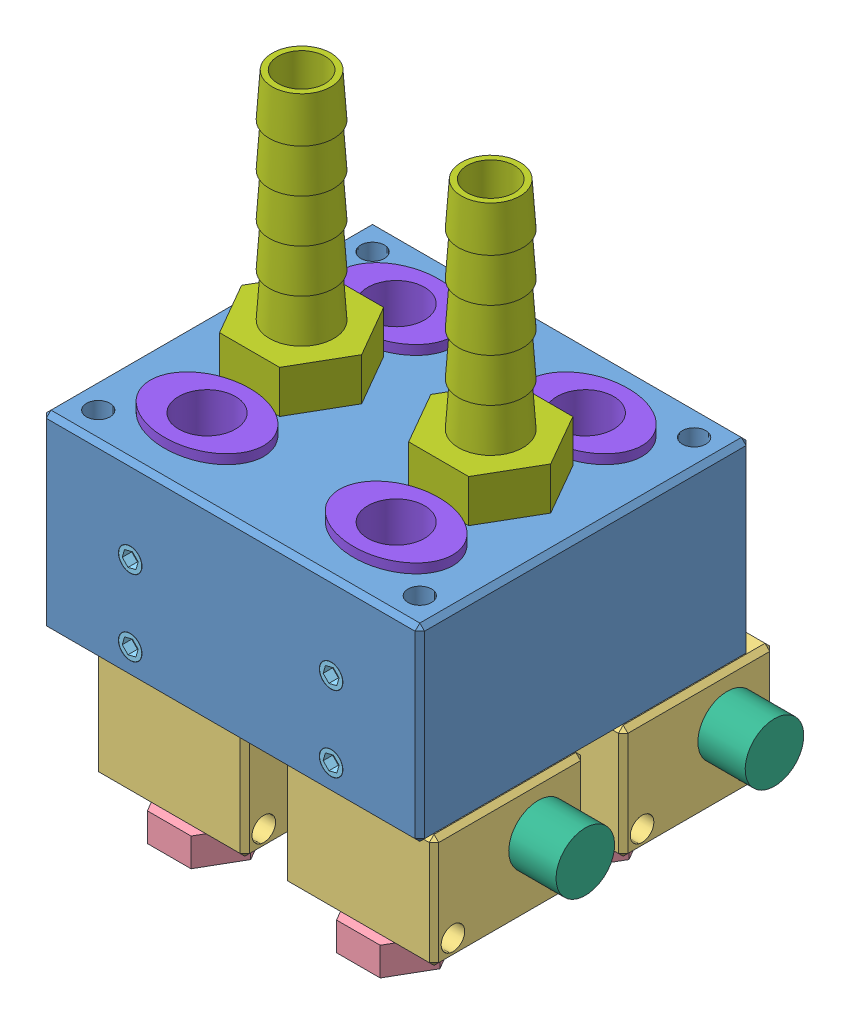
SolidWorks assembly Kraken, configuration Default. Lengths in mm.
Overall size (66 67 39.5).
35 component instances, 8 part files, 76 mates.
Components (placement in the parent):
- Kraken Cooling Block-1: Kraken Cooling Block [Default] at origin size (40 20 35)
- Kraken Heat Break-1: Kraken Heat Break [Default] at (-10 3.2 10) x (-0.959277 0 -0.282467) z (0.282467 0 -0.959277) size (7 20.6 7)
- E3D Heat Block-1: E3D Heat Block [Default] at (-10 -14.1 6) x (0 0 -1) z (1 0 0) size (16 12 16)
- E3D Nozzle-1: E3D Nozzle [Default] at (-10 -17.6 10) size (9.24 12.5 8)
- socket set screw cone point_am-2: socket set screw cone point_am [B18.3.6M - M3 x 0.5 x 3 Hex Socket Cone Pt. SS --N] at (-10 -14.1 4) x (0 1 0) z (0.271788 0 0.962357) size (3 3 3)
- cartridge heater-1: cartridge heater [Default] at (-12 -7.1 3) size (32 6.2 6.2)
- socket set screw cone point_am-4: socket set screw cone point_am [B18.3.6M - M3 x 0.5 x 3 Hex Socket Cone Pt. SS --N] at (10.6221 11 17.5) x (0 0 -1) z (0.271788 0.962357 0) size (3 3 3)
- socket set screw cone point_am-5: socket set screw cone point_am [B18.3.6M - M3 x 0.5 x 3 Hex Socket Cone Pt. SS --N] at (10.6221 3 17.5) x (0 0 -1) z (0.271788 0.962357 0) size (3 3 3)
- socket set screw cone point_am-6: socket set screw cone point_am [B18.3.6M - M3 x 0.5 x 3 Hex Socket Cone Pt. SS --N] at (-10.6221 11 17.5) x (0 0 -1) z (0.271788 0.962357 0) size (3 3 3)
- socket set screw cone point_am-7: socket set screw cone point_am [B18.3.6M - M3 x 0.5 x 3 Hex Socket Cone Pt. SS --N] at (-10.6221 3 17.5) x (0 0 -1) z (0.271788 0.962357 0) size (3 3 3)
- socket set screw cone point_am-8: socket set screw cone point_am [B18.3.6M - M3 x 0.5 x 3 Hex Socket Cone Pt. SS --N] at (-10.6221 3 -17.5) x (0 0 1) z (0.271788 -0.962357 0) size (3 3 3)
- socket set screw cone point_am-9: socket set screw cone point_am [B18.3.6M - M3 x 0.5 x 3 Hex Socket Cone Pt. SS --N] at (-10.6221 11 -17.5) x (0 0 1) z (0.271788 -0.962357 0) size (3 3 3)
- socket set screw cone point_am-10: socket set screw cone point_am [B18.3.6M - M3 x 0.5 x 3 Hex Socket Cone Pt. SS --N] at (10.6221 11 -17.5) x (0 0 1) z (0.271788 -0.962357 0) size (3 3 3)
- socket set screw cone point_am-11: socket set screw cone point_am [B18.3.6M - M3 x 0.5 x 3 Hex Socket Cone Pt. SS --N] at (10.6221 3 -17.5) x (0 0 1) z (0.271788 -0.962357 0) size (3 3 3)
- E3D Nozzle-5: E3D Nozzle [Default] at (10 -17.6 10) size (9.24 12.5 8)
- cartridge heater-5: cartridge heater [Default] at (12 -7.1 3) x (-1 0 0) z (0 0.924225 0.381849) size (32 6.2 6.2)
- socket set screw cone point_am-15: socket set screw cone point_am [B18.3.6M - M3 x 0.5 x 3 Hex Socket Cone Pt. SS --N] at (10 -14.1 4) x (0 1 0) z (0.271788 0 0.962357) size (3 3 3)
- E3D Heat Block-5: E3D Heat Block [Default] at (10 -14.1 6) x (0 0 -1) z (1 0 0) size (16 12 16)
- Kraken Heat Break-12: Kraken Heat Break [Default] at (10 3.2 10) x (-0.959277 0 -0.282467) z (0.282467 0 -0.959277) size (7 20.6 7)
- E3D Nozzle-6: E3D Nozzle [Default] at (10 -17.6 -10) size (9.24 12.5 8)
- cartridge heater-6: cartridge heater [Default] at (12 -7.1 -17) x (-1 0 0) z (0 0.924225 0.381849) size (32 6.2 6.2)
- socket set screw cone point_am-16: socket set screw cone point_am [B18.3.6M - M3 x 0.5 x 3 Hex Socket Cone Pt. SS --N] at (10 -14.1 -16) x (0 1 0) z (0.271788 0 0.962357) size (3 3 3)
- E3D Heat Block-6: E3D Heat Block [Default] at (10 -14.1 -14) x (0 0 -1) z (1 0 0) size (16 12 16)
- Kraken Heat Break-13: Kraken Heat Break [Default] at (10 3.2 -10) x (-0.959277 0 -0.282467) z (0.282467 0 -0.959277) size (7 20.6 7)
- E3D Nozzle-7: E3D Nozzle [Default] at (-10 -17.6 -10) size (9.24 12.5 8)
- cartridge heater-7: cartridge heater [Default] at (-12 -7.1 -17) size (32 6.2 6.2)
- socket set screw cone point_am-17: socket set screw cone point_am [B18.3.6M - M3 x 0.5 x 3 Hex Socket Cone Pt. SS --N] at (-10 -14.1 -16) x (0 1 0) z (0.271788 0 0.962357) size (3 3 3)
- E3D Heat Block-7: E3D Heat Block [Default] at (-10 -14.1 -14) x (0 0 -1) z (1 0 0) size (16 12 16)
- Kraken Heat Break-14: Kraken Heat Break [Default] at (-10 3.2 -10) x (-0.959277 0 -0.282467) z (0.282467 0 -0.959277) size (7 20.6 7)
- E3D Barbed fitting-1: E3D Barbed fitting [4810T221] at (-10 23.175 0) x (0 1 0) z (0 0 1) size (35.43 12.7 11)
- E3D Barbed fitting-2: E3D Barbed fitting [4810T221] at (10 23.175 0) x (0 1 0) z (-0.001728 0 0.999999) size (35.43 12.7 11)
- Kraken Compression Coupling-1: Kraken Compression Coupling [Default] at (10 20 -10) size (12 6.5 9)
- Kraken Compression Coupling-2: Kraken Compression Coupling [Default] at (-10 20 -10) size (12 6.5 9)
- Kraken Compression Coupling-3: Kraken Compression Coupling [Default] at (-10 20 10) size (12 6.5 9)
- Kraken Compression Coupling-4: Kraken Compression Coupling [Default] at (10 20 10) size (12 6.5 9)
Mates (geometry in assembly coordinates):
- Parallel1: parallel aligned: plane of Kraken Cooling Block-1 through (-20 20 17.5) normal (0 0 1); plane of E3D Heat Block-1 through (-2 -2.1 14) normal (0 0 1)
- Concentric10: concentric aligned: cylinder of E3D Heat Block-1 through (-10 -14.1 4) axis (0 -1 0) radius 1.25; cylinder of socket set screw cone point_am-2 through (-10 -26.8 4) axis (0 -1 0) radius 1.5
- Coincident13: coincident aligned: plane of E3D Heat Block-1 through (-10 -14.1 6) normal (0 -1 0); plane of socket set screw cone point_am-2 through (-10 -14.1 4) normal (0 -1 0)
- Concentric11: concentric anti-aligned: cylinder of E3D Heat Block-1 through (-18 -7.1 3) axis (1 0 0) radius 3.1; cylinder of cartridge heater-1 through (-23 -7.1 3) axis (-1 0 0) radius 3.1
- Concentric13: concentric aligned: cylinder of Kraken Cooling Block-1 through (10.6221 11 17.5) axis (0 0 1) radius 1.25; cylinder of socket set screw cone point_am-4 through (10.6221 11 30.2) axis (0 0 1) radius 1.5
- Coincident16: coincident aligned: plane of Kraken Cooling Block-1 through (-20 20 17.5) normal (0 0 1); plane of socket set screw cone point_am-4 through (10.6221 11 17.5) normal (0 0 1)
- Concentric14: concentric aligned: cylinder of Kraken Cooling Block-1 through (10.6221 3 17.5) axis (0 0 1) radius 1.25; cylinder of socket set screw cone point_am-5 through (10.6221 3 30.2) axis (0 0 1) radius 1.5
- Coincident17: coincident aligned: plane of Kraken Cooling Block-1 through (-20 20 17.5) normal (0 0 1); plane of socket set screw cone point_am-5 through (10.6221 3 17.5) normal (0 0 1)
- Concentric15: concentric aligned: cylinder of Kraken Cooling Block-1 through (-10.6221 11 17.5) axis (0 0 1) radius 1.25; cylinder of socket set screw cone point_am-6 through (-10.6221 11 30.2) axis (0 0 1) radius 1.5
- Coincident18: coincident aligned: plane of Kraken Cooling Block-1 through (-20 20 17.5) normal (0 0 1); plane of socket set screw cone point_am-6 through (-10.6221 11 17.5) normal (0 0 1)
- Concentric16: concentric aligned: cylinder of Kraken Cooling Block-1 through (-10.6221 3 17.5) axis (0 0 1) radius 1.25; cylinder of socket set screw cone point_am-7 through (-10.6221 3 30.2) axis (0 0 1) radius 1.5
- Coincident19: coincident aligned: plane of Kraken Cooling Block-1 through (-20 20 17.5) normal (0 0 1); plane of socket set screw cone point_am-7 through (-10.6221 3 17.5) normal (0 0 1)
- Concentric17: concentric aligned: cylinder of Kraken Cooling Block-1 through (-10.6221 3 -17.5) axis (0 0 -1) radius 1.25; cylinder of socket set screw cone point_am-8 through (-10.6221 3 -30.2) axis (0 0 -1) radius 1.5
- Coincident20: coincident aligned: plane of Kraken Cooling Block-1 through (-20 20 -17.5) normal (0 0 -1); plane of socket set screw cone point_am-8 through (-10.6221 3 -17.5) normal (0 0 -1)
- Concentric18: concentric aligned: cylinder of Kraken Cooling Block-1 through (-10.6221 11 -17.5) axis (0 0 -1) radius 1.25; cylinder of socket set screw cone point_am-9 through (-10.6221 11 -30.2) axis (0 0 -1) radius 1.5
- Coincident21: coincident aligned: plane of Kraken Cooling Block-1 through (-20 20 -17.5) normal (0 0 -1); plane of socket set screw cone point_am-9 through (-10.6221 11 -17.5) normal (0 0 -1)
- Concentric19: concentric aligned: cylinder of Kraken Cooling Block-1 through (10.6221 11 -17.5) axis (0 0 -1) radius 1.25; cylinder of socket set screw cone point_am-10 through (10.6221 11 -30.2) axis (0 0 -1) radius 1.5
- Coincident22: coincident aligned: plane of Kraken Cooling Block-1 through (-20 20 -17.5) normal (0 0 -1); plane of socket set screw cone point_am-10 through (10.6221 11 -17.5) normal (0 0 -1)
- Concentric20: concentric aligned: cylinder of Kraken Cooling Block-1 through (10.6221 3 -17.5) axis (0 0 -1) radius 1.25; cylinder of socket set screw cone point_am-11 through (10.6221 3 -30.2) axis (0 0 -1) radius 1.5
- Coincident23: coincident aligned: plane of Kraken Cooling Block-1 through (-20 20 -17.5) normal (0 0 -1); plane of socket set screw cone point_am-11 through (10.6221 3 -17.5) normal (0 0 -1)
- Distance1: distance = 1 mm aligned: plane of cartridge heater-1 through (-1 -7.1 0.4) normal (1 0 0); plane of E3D Heat Block-1 through (-2 -2.1 14) normal (1 0 0)
- Concentric21: concentric aligned: cylinder of Kraken Heat Break-1 through (-10 -7.1 10) axis (0 -1 0) radius 3; cylinder of E3D Nozzle-1 through (-10 -19.6 10) axis (0 -1 0) radius 3
- Coincident25: coincident anti-aligned: plane of Kraken Heat Break-1 through (-10.9593 -7.1 9.7175) normal (0 -1 0); plane of E3D Nozzle-1 through (-10 -7.1 10) normal (0 1 0)
- Concentric22: concentric anti-aligned: cylinder of Kraken Heat Break-1 through (-10 -7.1 10) axis (0 -1 0) radius 3; cylinder of E3D Heat Block-1 through (-10 -2.1 10) axis (0 1 0) radius 2.5
- Coincident26: coincident aligned: plane of Kraken Heat Break-1 through (-12.8778 -2.1 9.1526) normal (0 1 0); plane of E3D Heat Block-1 through (-10 -2.1 6) normal (0 1 0)
- Concentric23: concentric aligned: cylinder of Kraken Cooling Block-1 through (-10 0 10) axis (0 -1 0) radius 3.5; cylinder of Kraken Heat Break-1 through (-10 -7.1 10) axis (0 -1 0) radius 3.5
- Coincident27: coincident aligned: plane of Kraken Cooling Block-1 through (0 0 0) normal (0 -1 0); plane of Kraken Heat Break-1 through (-11.343 0 9.6045) normal (0 -1 0)
- Coincident39: coincident aligned: plane of Kraken Cooling Block-1 through (0 0 0) normal (0 -1 0); plane of Kraken Heat Break-1 through (-11.343 0 9.6045) normal (0 -1 0)
- Concentric38: concentric aligned: cylinder of socket set screw cone point_am-15 through (10 -26.8 4) axis (0 -1 0) radius 1.5; cylinder of E3D Heat Block-5 through (10 -14.1 4) axis (0 -1 0) radius 1.25
- Coincident40: coincident aligned: plane of socket set screw cone point_am-15 through (10 -14.1 4) normal (0 -1 0); plane of E3D Heat Block-5 through (10 -14.1 6) normal (0 -1 0)
- Concentric39: concentric aligned: cylinder of cartridge heater-5 through (23 -7.1 3) axis (1 0 0) radius 3.1; cylinder of E3D Heat Block-5 through (2 -7.1 3) axis (1 0 0) radius 3.1
- Distance5: distance = 1 mm aligned: plane of cartridge heater-5 through (1 -9.503 2.0072) normal (-1 0 0); plane of E3D Heat Block-5 through (2 -2.1 14) normal (-1 0 0)
- Concentric40: concentric aligned: cylinder of E3D Nozzle-5 through (10 -19.6 10) axis (0 -1 0) radius 3; cylinder of Kraken Heat Break-12 through (10 -7.1 10) axis (0 -1 0) radius 3
- Coincident41: coincident anti-aligned: plane of E3D Nozzle-5 through (10 -7.1 10) normal (0 1 0); plane of Kraken Heat Break-12 through (9.0407 -7.1 9.7175) normal (0 -1 0)
- Concentric41: concentric anti-aligned: cylinder of E3D Heat Block-5 through (10 -2.1 10) axis (0 1 0) radius 2.5; cylinder of Kraken Heat Break-12 through (10 -7.1 10) axis (0 -1 0) radius 3
- Coincident42: coincident aligned: plane of E3D Heat Block-5 through (10 -2.1 6) normal (0 1 0); plane of Kraken Heat Break-12 through (7.1222 -2.1 9.1526) normal (0 1 0)
- Parallel5: parallel aligned: plane of Kraken Cooling Block-1 through (-20 20 17.5) normal (0 0 1); plane of E3D Heat Block-5 through (18 -2.1 14) normal (0 0 1)
- Coincident43: coincident aligned: plane of Kraken Cooling Block-1 through (0 0 0) normal (0 -1 0); plane of Kraken Heat Break-12 through (8.657 0 9.6045) normal (0 -1 0)
- Coincident44: coincident aligned: plane of Kraken Cooling Block-1 through (0 0 0) normal (0 -1 0); plane of Kraken Heat Break-12 through (8.657 0 9.6045) normal (0 -1 0)
- Concentric42: concentric aligned: cylinder of Kraken Cooling Block-1 through (10 0 10) axis (0 -1 0) radius 3.5; cylinder of Kraken Heat Break-12 through (10 -7.1 10) axis (0 -1 0) radius 3.5
- Concentric43: concentric aligned: cylinder of socket set screw cone point_am-16 through (10 -26.8 -16) axis (0 -1 0) radius 1.5; cylinder of E3D Heat Block-6 through (10 -14.1 -16) axis (0 -1 0) radius 1.25
- Coincident45: coincident aligned: plane of socket set screw cone point_am-16 through (10 -14.1 -16) normal (0 -1 0); plane of E3D Heat Block-6 through (10 -14.1 -14) normal (0 -1 0)
- Concentric44: concentric aligned: cylinder of cartridge heater-6 through (23 -7.1 -17) axis (1 0 0) radius 3.1; cylinder of E3D Heat Block-6 through (2 -7.1 -17) axis (1 0 0) radius 3.1
- Distance6: distance = 1 mm aligned: plane of cartridge heater-6 through (1 -9.503 -17.9928) normal (-1 0 0); plane of E3D Heat Block-6 through (2 -2.1 -6) normal (-1 0 0)
- Concentric45: concentric aligned: cylinder of E3D Nozzle-6 through (10 -19.6 -10) axis (0 -1 0) radius 3; cylinder of Kraken Heat Break-13 through (10 -7.1 -10) axis (0 -1 0) radius 3
- Coincident46: coincident anti-aligned: plane of E3D Nozzle-6 through (10 -7.1 -10) normal (0 1 0); plane of Kraken Heat Break-13 through (9.0407 -7.1 -10.2825) normal (0 -1 0)
- Concentric46: concentric anti-aligned: cylinder of E3D Heat Block-6 through (10 -2.1 -10) axis (0 1 0) radius 2.5; cylinder of Kraken Heat Break-13 through (10 -7.1 -10) axis (0 -1 0) radius 3
- Coincident47: coincident aligned: plane of E3D Heat Block-6 through (10 -2.1 -14) normal (0 1 0); plane of Kraken Heat Break-13 through (7.1222 -2.1 -10.8474) normal (0 1 0)
- Parallel6: parallel aligned: plane of Kraken Cooling Block-1 through (-20 20 17.5) normal (0 0 1); plane of E3D Heat Block-6 through (18 -2.1 -6) normal (0 0 1)
- Concentric47: concentric aligned: cylinder of Kraken Cooling Block-1 through (10 0 -10) axis (0 -1 0) radius 3.5; cylinder of Kraken Heat Break-13 through (10 -7.1 -10) axis (0 -1 0) radius 3.5
- Coincident48: coincident aligned: plane of Kraken Cooling Block-1 through (0 0 0) normal (0 -1 0); plane of Kraken Heat Break-13 through (8.657 0 -10.3955) normal (0 -1 0)
- Coincident49: coincident aligned: plane of Kraken Cooling Block-1 through (0 0 0) normal (0 -1 0); plane of Kraken Heat Break-13 through (8.657 0 -10.3955) normal (0 -1 0)
- Concentric48: concentric aligned: cylinder of socket set screw cone point_am-17 through (-10 -26.8 -16) axis (0 -1 0) radius 1.5; cylinder of E3D Heat Block-7 through (-10 -14.1 -16) axis (0 -1 0) radius 1.25
- Coincident50: coincident aligned: plane of socket set screw cone point_am-17 through (-10 -14.1 -16) normal (0 -1 0); plane of E3D Heat Block-7 through (-10 -14.1 -14) normal (0 -1 0)
- Concentric49: concentric anti-aligned: cylinder of cartridge heater-7 through (-23 -7.1 -17) axis (-1 0 0) radius 3.1; cylinder of E3D Heat Block-7 through (-18 -7.1 -17) axis (1 0 0) radius 3.1
- Distance7: distance = 1 mm aligned: plane of cartridge heater-7 through (-1 -7.1 -19.6) normal (1 0 0); plane of E3D Heat Block-7 through (-2 -2.1 -6) normal (1 0 0)
- Concentric50: concentric aligned: cylinder of E3D Nozzle-7 through (-10 -19.6 -10) axis (0 -1 0) radius 3; cylinder of Kraken Heat Break-14 through (-10 -7.1 -10) axis (0 -1 0) radius 3
- Coincident51: coincident anti-aligned: plane of E3D Nozzle-7 through (-10 -7.1 -10) normal (0 1 0); plane of Kraken Heat Break-14 through (-10.9593 -7.1 -10.2825) normal (0 -1 0)
- Concentric51: concentric anti-aligned: cylinder of E3D Heat Block-7 through (-10 -2.1 -10) axis (0 1 0) radius 2.5; cylinder of Kraken Heat Break-14 through (-10 -7.1 -10) axis (0 -1 0) radius 3
- Coincident52: coincident aligned: plane of E3D Heat Block-7 through (-10 -2.1 -14) normal (0 1 0); plane of Kraken Heat Break-14 through (-12.8778 -2.1 -10.8474) normal (0 1 0)
- Parallel7: parallel aligned: plane of Kraken Cooling Block-1 through (-20 20 17.5) normal (0 0 1); plane of E3D Heat Block-7 through (-2 -2.1 -6) normal (0 0 1)
- Concentric52: concentric aligned: cylinder of Kraken Cooling Block-1 through (-10 0 -10) axis (0 -1 0) radius 3.5; cylinder of Kraken Heat Break-14 through (-10 -7.1 -10) axis (0 -1 0) radius 3.5
- Coincident53: coincident aligned: plane of Kraken Cooling Block-1 through (0 0 0) normal (0 -1 0); plane of Kraken Heat Break-14 through (-11.343 0 -10.3955) normal (0 -1 0)
- Coincident54: coincident aligned: plane of Kraken Cooling Block-1 through (0 0 0) normal (0 -1 0); plane of Kraken Heat Break-14 through (-11.343 0 -10.3955) normal (0 -1 0)
- Concentric53: concentric anti-aligned: cylinder of Kraken Cooling Block-1 through (-10 20 0) axis (0 1 0) radius 4.4; cylinder of E3D Barbed fitting-1 through (-10 24.5 0) axis (0 -1 0) radius 2.5
- Coincident55: coincident anti-aligned: plane of Kraken Cooling Block-1 through (0 20 0) normal (0 1 0); plane of E3D Barbed fitting-1 through (-16.3509 20 0) normal (0 -1 0)
- Concentric54: concentric anti-aligned: cylinder of Kraken Cooling Block-1 through (10 20 0) axis (0 1 0) radius 4.4; cylinder of E3D Barbed fitting-2 through (10 24.5 0) axis (0 -1 0) radius 2.5
- Coincident56: coincident anti-aligned: plane of Kraken Cooling Block-1 through (0 20 0) normal (0 1 0); plane of E3D Barbed fitting-2 through (3.6492 20 -0.011) normal (0 -1 0)
- Concentric55: concentric aligned: cylinder of Kraken Cooling Block-1 through (10 20 -10) axis (0 1 0) radius 4; cylinder of Kraken Compression Coupling-1 through (10 14.5 -10) axis (0 1 0) radius 4
- Coincident57: coincident anti-aligned: plane of Kraken Cooling Block-1 through (0 20 0) normal (0 1 0); plane of Kraken Compression Coupling-1 through (10 20 -10) normal (0 -1 0)
- Concentric56: concentric aligned: cylinder of Kraken Cooling Block-1 through (-10 20 -10) axis (0 1 0) radius 4; cylinder of Kraken Compression Coupling-2 through (-10 14.5 -10) axis (0 1 0) radius 4
- Coincident58: coincident anti-aligned: plane of Kraken Cooling Block-1 through (0 20 0) normal (0 1 0); plane of Kraken Compression Coupling-2 through (-10 20 -10) normal (0 -1 0)
- Concentric57: concentric aligned: cylinder of Kraken Cooling Block-1 through (-10 20 10) axis (0 1 0) radius 4; cylinder of Kraken Compression Coupling-3 through (-10 14.5 10) axis (0 1 0) radius 4
- Coincident59: coincident anti-aligned: plane of Kraken Cooling Block-1 through (0 20 0) normal (0 1 0); plane of Kraken Compression Coupling-3 through (-10 20 10) normal (0 -1 0)
- Concentric58: concentric aligned: cylinder of Kraken Cooling Block-1 through (10 20 10) axis (0 1 0) radius 4; cylinder of Kraken Compression Coupling-4 through (10 14.5 10) axis (0 1 0) radius 4
- Coincident60: coincident anti-aligned: plane of Kraken Cooling Block-1 through (0 20 0) normal (0 1 0); plane of Kraken Compression Coupling-4 through (10 20 10) normal (0 -1 0)
